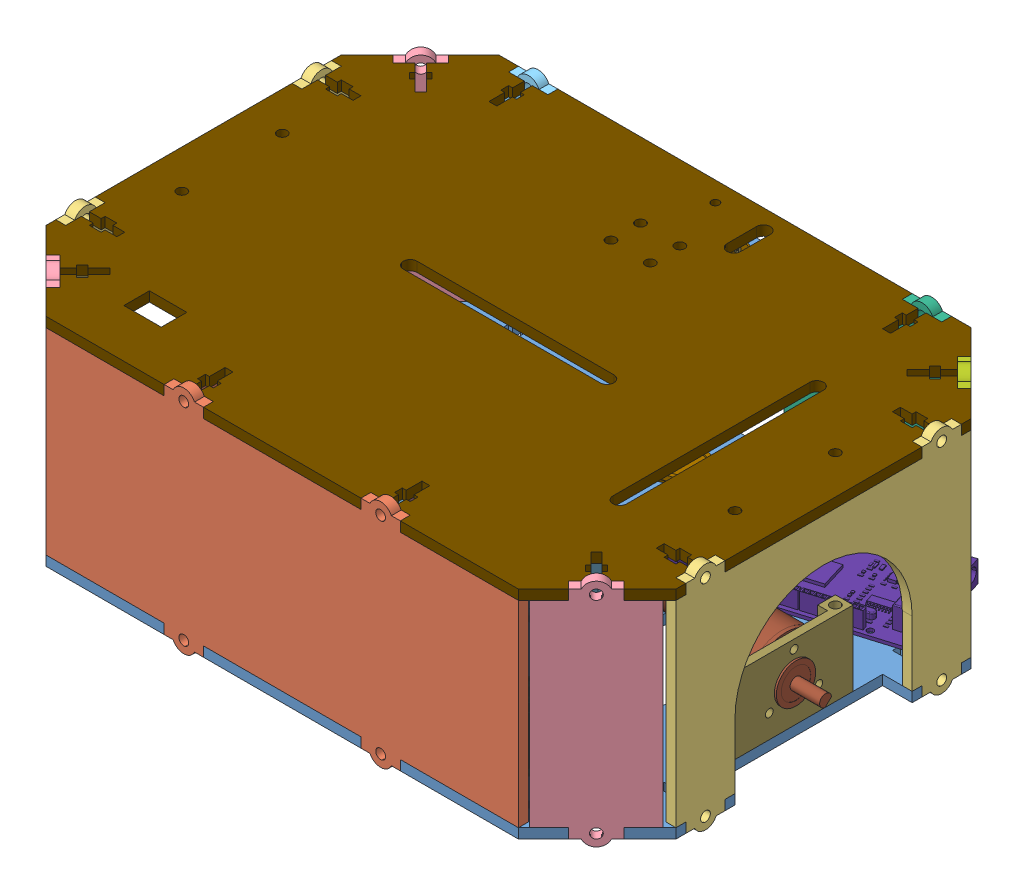
SolidWorks assembly Conception finale, configuration Default. Lengths in mm.
Overall size (322 125.9 232.7).
149 component instances, 109 part files, 84 mates.
Components (placement in the parent):
- base-1: base [Default] at (144.9851 187.411 243.3033) size (320 5 230)
- backwall-1: backwall [Default] at (144.9851 242.411 353.3033) size (240 117 5)
- encoderwall-1: encoderwall [Default] at (-15.0149 242.411 243.3033) x (0 0 -1) z (1 0 0) size (150 117 5)
- encoderwall-2: encoderwall [Default] at (299.9851 242.411 243.3033) x (0 0 -1) z (1 0 0) size (150 117 5)
- coinwall-1: coinwall [Default] at (5.1861 242.411 338.5044) x (-0.707107 0 -0.707107) z (0.707107 0 -0.707107) size (48 117 5)
- coinwall-3: coinwall [Default] at (8.7216 242.411 151.6379) x (-0.707107 0 0.707107) z (-0.707107 0 -0.707107) size (48 117 5)
- frontwall-1: frontwall [Default] at (44.9851 242.411 128.3033) size (40 117 5)
- frontwallleft-1: frontwallleft [Default] at (219.9851 242.411 133.3033) x (-1 0 0) z (0 0 -1) size (90 117 5)
- coinwallarduino-1: coinwallarduino [Default] at (284.7841 242.411 148.1023) x (0.707107 0 0.707107) z (-0.707107 0 0.707107) size (48 88.5 5)
- coinwall-5: coinwall [Default] at (281.2485 242.411 334.9688) x (0.707107 0 -0.707107) z (0.707107 0 0.707107) size (48 117 5)
- scroller support-1: scroller support [Default] at (144.9336 182.411 158.2438) x (0.999996 0 -0.002768) z (0.002768 0 0.999996) size (63 5 43)
- scroller support-2: scroller support [Default] at (144.9336 182.411 328.3568) x (0.999997 0 0.002484) z (-0.002484 0 0.999997) size (63 5 43)
- W420 Universal Steel Ball Caster-1: W420 Universal Steel Ball Caster [Default] at (126.0797 215.1451 204.8926) x (0.999966 0 -0.008254) z (-0.008254 0 -0.999966) size (50.67 20.4 23.62)
  - plastic stand-1: plastic stand [Default] at (18.2421 19.7342 46.6095) x (1 0 0) z (0 1 0) size (50.67 23.62 17.5)
  - ball-1: ball [Default] at (18.2421 32.6342 46.6095) size (15 15 15)
- W420 Universal Steel Ball Caster-2: W420 Universal Steel Ball Caster [Default] at (126.0357 215.1451 374.895) x (0.999973 0 -0.007309) z (-0.007309 0 -0.999973) size (50.67 20.4 23.62)
  - plastic stand-1: plastic stand [Default] at (18.2421 19.7342 46.6095) x (1 0 0) z (0 1 0) size (50.67 23.62 17.5)
  - ball-1: ball [Default] at (18.2421 32.6342 46.6095) size (15 15 15)
- Encoder - YUMO E6B2-CWZ3E-1: Encoder - YUMO E6B2-CWZ3E [Default] at (3.9851 211.411 243.3033) x (0 0.688167 -0.725552) z (1 0 0) size (40 72 59.05)
- support encoder-1: support encoder [Défaut] at (-4.8153 200.5473 210.7418) x (0 0 1) z (0 -1 0) size (60 9 38)
- Encoder - YUMO E6B2-CWZ3E-2: Encoder - YUMO E6B2-CWZ3E [Default] at (285.9851 211.411 243.3033) x (0 -0.688167 0.725552) z (-1 0 0) size (40 72 59.05)
- support encoder-2: support encoder [Défaut] at (294.7855 222.2747 210.7418) x (0 0 1) z (0 1 0) size (60 9 38)
- dc-1: dc [Default] at (184.7554 215.4273 248.1083) x (-0.00085 0.96122 -0.275783) z (0.999995 0 -0.003082) size (25 25 65.5)
- L-2: L [Default] at (176.0083 192.411 265.2813) x (-0.999995 0 0.003082) z (-0.003082 0 -0.999995) size (31 40 30)
- dc-2: dc [Default] at (105.2148 215.4273 248.1083) x (0.00085 0.96122 -0.275783) z (-0.999995 0 -0.003082) size (25 25 65.5)
- L-3: L [Default] at (114.0543 192.411 235.2815) x (0.999995 0 0.003082) z (-0.003082 0 0.999995) size (31 40 30)
- L298N Motor Driver.step-1: L298N Motor Driver.step [Default] at (232.0699 192.411 311.1269) x (0.999844 0 0.017659) z (-0.017659 0 0.999844) size (43.5 26 43.5)
- 3 Battery Holder With Batteries.step-1: 3 Battery Holder With Batteries.step [Default] at (69.3789 192.411 398.8726) x (1 0 0) z (0 1 0) size (77.98 59.63 24.74)
- Arduino_Mega.step-1: Arduino_Mega.step [Default] at (269.8515 192.411 130.3971) x (-0.957328 0 0.289003) z (-0.289003 0 -0.957328) size (109.3 15.6 54)
- s9af-1: s9af [Default] at (144.9851 292.411 243.3033) size (320 5 230)
- camsupport2-1: camsupport2 [Default] at (144.9851 259.911 156.3033) x (0 -1 0) z (1 0 0) size (55 63 40.58)
- ESP32-cam.step-1: ESP32-cam.step [Default] at (159.1738 242.9456 134.2033) x (-0.999726 -0.02341 0) z (0 0 -1) size (27 40 16.8)
  - pins.step-1: pins.step [Default] at origin size (25.4 20.32 11.2)
    - Body001.step-1: Body001.step [Default] at (2.07 17.64 0) size (2.54 2.54 11.2)
    - Body001.step-2: Body001.step [Default] at (2.07 20.18 0) size (2.54 2.54 11.2)
    - Body001.step-3: Body001.step [Default] at (2.07 22.72 0) size (2.54 2.54 11.2)
    - Body001.step-4: Body001.step [Default] at (2.07 25.26 0) size (2.54 2.54 11.2)
    - Body001.step-5: Body001.step [Default] at (2.07 27.8 0) size (2.54 2.54 11.2)
    - Body001.step-6: Body001.step [Default] at (2.07 30.34 0) size (2.54 2.54 11.2)
    - Body001.step-7: Body001.step [Default] at (2.07 32.88 0) size (2.54 2.54 11.2)
    - Body001.step-8: Body001.step [Default] at (2.07 35.42 0) size (2.54 2.54 11.2)
    - Body001.step-9: Body001.step [Default] at (24.93 17.64 0) size (2.54 2.54 11.2)
    - Body001.step-10: Body001.step [Default] at (24.93 20.18 0) size (2.54 2.54 11.2)
    - Body001.step-11: Body001.step [Default] at (24.93 22.72 0) size (2.54 2.54 11.2)
    - Body001.step-12: Body001.step [Default] at (24.93 25.26 0) size (2.54 2.54 11.2)
    - Body001.step-13: Body001.step [Default] at (24.93 27.8 0) size (2.54 2.54 11.2)
    - Body001.step-14: Body001.step [Default] at (24.93 30.34 0) size (2.54 2.54 11.2)
    - Body001.step-15: Body001.step [Default] at (24.93 32.88 0) size (2.54 2.54 11.2)
    - Body001.step-16: Body001.step [Default] at (24.93 35.42 0) size (2.54 2.54 11.2)
  - ESP32-S.step-1: ESP32-S.step [Default] at (4.5 25.2 0) x (1 0 0) z (0 0 -1) size (18 19.2 3.2)
    - PCB_ESP32-S.step-1: PCB_ESP32-S.step [Default] at origin size (18 19.2 2.02)
      - DesignRootModel^PCB_ESP32-S2-SOLO-U_V1_ESP32-S2-SOLO-U_V1.step-1: DesignRootModel^PCB_ESP32-S2-SOLO-U_V1_ESP32-S2-SOLO-U_V1.step [Default] at origin size (18 19.2 0.73)
        - uid__2363^DesignRootModel_PCB_ESP32-S2-SOLO-U_V1_ESP32-S2-SOLO-U_V1.step-1: uid__2363^DesignRootModel_PCB_ESP32-S2-SOLO-U_V1_ESP32-S2-SOLO-U_V1.step [Default] at origin size (18 19.2 0.73)
      - Submodel-IPEX_3P_part^DesignRootModel_PCB_ESP32-S2-SOLO-U_V1_ESP32-S2-SOLO-U_V1.step-1: Submodel-IPEX_3P_part^DesignRootModel_PCB_ESP32-S2-SOLO-U_V1_ESP32-S2-SOLO-U_V1.step [Default] at (15.0063 16.7434 0.7992) x (0 -1 0) z (0 0 1) size (3.01 3.11 1.26)
        - 20279-001E-01C RECEPTACLE R9 STEP ALL.STEP^Submodel-IPEX_3P_part_DesignRootModel_PCB_ESP32-S2-SOLO-U_V1_ESP32-S2-SOLO-U_V1.step-1: 20279-001E-01C RECEPTACLE R9 STEP ALL.STEP^Submodel-IPEX_3P_part_DesignRootModel_PCB_ESP32-S2-SOLO-U_V1_ESP32-S2-SOLO-U_V1.step [Default] x (1 0 0) z (0 -1 0) size (3.01 1.26 3.11)
          - 20279-001E-01C RECEPTACLE R9 STEP ALL.STEP^20279-001E-01C RECEPTACLE R9 STEP ALL.STEP_Submodel-IPEX_3P_part_DesignRootModel_PCB_ESP32-S2-SOLO-U_V1_ESP32-S2-SOLO-U_V003.step-1: 20279-001E-01C RECEPTACLE R9 STEP ALL.STEP^20279-001E-01C RECEPTACLE R9 STEP ALL.STEP_Submodel-IPEX_3P_part_DesignRootModel_PCB_ESP32-S2-SOLO-U_V1_ESP32-S2-SOLO-U_V003.step [Default] at origin size (3.01 1.26 3.11)
            - 20279-001E-01C RECEPTACLE R9 STEP ALL.STEP^20279-001E-01C RECEPTACLE R9 STEP ALL.STEP_Submodel-IPEX_3P_part_DesignRootModel_PCB_ESP32-S2-SOLO-U_V1_ESP32-S2-SOLO-U_V1.step-1: 20279-001E-01C RECEPTACLE R9 STEP ALL.STEP^20279-001E-01C RECEPTACLE R9 STEP ALL.STEP_Submodel-IPEX_3P_part_DesignRootModel_PCB_ESP32-S2-SOLO-U_V1_ESP32-S2-SOLO-U_V1.step [Default] at origin size (2.61 0.01 2.61)
            - 20279-001E-01C RECEPTACLE R9 STEP ALL.STEP^20279-001E-01C RECEPTACLE R9 STEP ALL.STEP_Submodel-IPEX_3P_part_DesignRootModel_PCB_ESP32-S2-SOLO-U_V1_ESP32-S2-SOLO-U_V002.step-1: 20279-001E-01C RECEPTACLE R9 STEP ALL.STEP^20279-001E-01C RECEPTACLE R9 STEP ALL.STEP_Submodel-IPEX_3P_part_DesignRootModel_PCB_ESP32-S2-SOLO-U_V1_ESP32-S2-SOLO-U_V002.step [Default] at origin size (3.01 1.26 3.11)
      - uid__1-263^DesignRootModel_PCB_ESP32-S2-SOLO-U_V1_ESP32-S2-SOLO-U_V1.step-1: uid__1-263^DesignRootModel_PCB_ESP32-S2-SOLO-U_V1_ESP32-S2-SOLO-U_V1.step [Default] at origin size (2.2 0.95 0.03)
      - uid__1-264^DesignRootModel_PCB_ESP32-S2-SOLO-U_V1_ESP32-S2-SOLO-U_V1.step-1: uid__1-264^DesignRootModel_PCB_ESP32-S2-SOLO-U_V1_ESP32-S2-SOLO-U_V1.step [Default] at origin size (2.2 0.95 0.03)
    - pad.step-1: pad.step [Default] at (0 18.01 0.0349) x (1 0 0) z (0 -1 0) size (0.85 0.8 0.9)
    - pad001.step-1: pad001.step [Default] at (0 16.74 0.0349) x (1 0 0) z (0 -1 0) size (0.85 0.8 0.9)
    - pad002.step-1: pad002.step [Default] at (0 15.47 0.0349) x (1 0 0) z (0 -1 0) size (0.85 0.8 0.9)
    - pad003.step-1: pad003.step [Default] at (0 14.2 0.0349) x (1 0 0) z (0 -1 0) size (0.85 0.8 0.9)
    - pad004.step-1: pad004.step [Default] at (0 12.93 0.0349) x (1 0 0) z (0 -1 0) size (0.85 0.8 0.9)
    - pad005.step-1: pad005.step [Default] at (0 11.66 0.0349) x (1 0 0) z (0 -1 0) size (0.85 0.8 0.9)
    - pad006.step-1: pad006.step [Default] at (0 10.39 0.0349) x (1 0 0) z (0 -1 0) size (0.85 0.8 0.9)
    - pad007.step-1: pad007.step [Default] at (0 9.12 0.0349) x (1 0 0) z (0 -1 0) size (0.85 0.8 0.9)
    - pad008.step-1: pad008.step [Default] at (0 7.85 0.0349) x (1 0 0) z (0 -1 0) size (0.85 0.8 0.9)
    - pad009.step-1: pad009.step [Default] at (0 6.58 0.0349) x (1 0 0) z (0 -1 0) size (0.85 0.8 0.9)
    - pad010.step-1: pad010.step [Default] at (0 5.31 0.0349) x (1 0 0) z (0 -1 0) size (0.85 0.8 0.9)
    - pad011.step-1: pad011.step [Default] at (0 4.04 0.0349) x (1 0 0) z (0 -1 0) size (0.85 0.8 0.9)
    - pad012.step-1: pad012.step [Default] at (0 2.77 0.0349) x (1 0 0) z (0 -1 0) size (0.85 0.8 0.9)
    - pad013.step-1: pad013.step [Default] at (0 1.5 0.0349) x (1 0 0) z (0 -1 0) size (0.85 0.8 0.9)
    - pad014.step-1: pad014.step [Default] at (2.015 0 0.0343) x (0 1 0) z (1 0 0) size (0.85 0.8 0.9)
    - pad015.step-1: pad015.step [Default] at (3.285 0 0.0343) x (0 1 0) z (1 0 0) size (0.85 0.8 0.9)
    - pad016.step-1: pad016.step [Default] at (4.555 0 0.0343) x (0 1 0) z (1 0 0) size (0.85 0.8 0.9)
    - pad017.step-1: pad017.step [Default] at (5.825 0 0.0343) x (0 1 0) z (1 0 0) size (0.85 0.8 0.9)
    - pad018.step-1: pad018.step [Default] at (7.095 0 0.0343) x (0 1 0) z (1 0 0) size (0.85 0.8 0.9)
    - pad019.step-1: pad019.step [Default] at (8.365 0 0.0343) x (0 1 0) z (1 0 0) size (0.85 0.8 0.9)
    - pad020.step-1: pad020.step [Default] at (9.635 0 0.0343) x (0 1 0) z (1 0 0) size (0.85 0.8 0.9)
    - pad021.step-1: pad021.step [Default] at (10.905 0 0.0343) x (0 1 0) z (1 0 0) size (0.85 0.8 0.9)
    - pad022.step-1: pad022.step [Default] at (12.175 0 0.0343) x (0 1 0) z (1 0 0) size (0.85 0.8 0.9)
    - pad023.step-1: pad023.step [Default] at (13.445 0 0.0343) x (0 1 0) z (1 0 0) size (0.85 0.8 0.9)
    - pad024.step-1: pad024.step [Default] at (14.715 0 0.0343) x (0 1 0) z (1 0 0) size (0.85 0.8 0.9)
    - pad025.step-1: pad025.step [Default] at (15.985 0 0.0343) x (0 1 0) z (1 0 0) size (0.85 0.8 0.9)
    - pad026.step-1: pad026.step [Default] at (18 1.5 0.0343) x (-1 0 0) z (0 1 0) size (0.85 0.8 0.9)
    - pad027.step-1: pad027.step [Default] at (18 2.77 0.0343) x (-1 0 0) z (0 1 0) size (0.85 0.8 0.9)
    - pad028.step-1: pad028.step [Default] at (18 4.04 0.0343) x (-1 0 0) z (0 1 0) size (0.85 0.8 0.9)
    - pad029.step-1: pad029.step [Default] at (18 5.31 0.0343) x (-1 0 0) z (0 1 0) size (0.85 0.8 0.9)
    - pad030.step-1: pad030.step [Default] at (18 6.58 0.0343) x (-1 0 0) z (0 1 0) size (0.85 0.8 0.9)
    - pad031.step-1: pad031.step [Default] at (18 7.85 0.0343) x (-1 0 0) z (0 1 0) size (0.85 0.8 0.9)
    - pad032.step-1: pad032.step [Default] at (18 9.12 0.0343) x (-1 0 0) z (0 1 0) size (0.85 0.8 0.9)
    - pad033.step-1: pad033.step [Default] at (18 10.39 0.0343) x (-1 0 0) z (0 1 0) size (0.85 0.8 0.9)
    - pad034.step-1: pad034.step [Default] at (18 11.66 0.0343) x (-1 0 0) z (0 1 0) size (0.85 0.8 0.9)
    - pad035.step-1: pad035.step [Default] at (18 12.93 0.0343) x (-1 0 0) z (0 1 0) size (0.85 0.8 0.9)
    - pad036.step-1: pad036.step [Default] at (18 14.2 0.0343) x (-1 0 0) z (0 1 0) size (0.85 0.8 0.9)
    - pad037.step-1: pad037.step [Default] at (18 15.47 0.0343) x (-1 0 0) z (0 1 0) size (0.85 0.8 0.9)
    - pad038.step-1: pad038.step [Default] at (18 16.74 0.0343) x (-1 0 0) z (0 1 0) size (0.85 0.8 0.9)
    - pad039.step-1: pad039.step [Default] at (18 18.01 0.0343) x (-1 0 0) z (0 1 0) size (0.85 0.8 0.9)
    - ESP32-WROOM-32U_Shieldingcase_20210312.step-1: ESP32-WROOM-32U_Shieldingcase_20210312.step [Default] at (1.27 1.1 0.7993) size (15.65 17.5 2.4)
  - MicroSD slot SMD.step-1: MicroSD slot SMD.step [Default] at (13.5 32.5 0.9) size (17.2 14.8 1.8)
    - Array.step-1: Array.step [Default] at origin size (9.49 0.5 0.62)
      - Body003.step-1: Body003.step [Default] at (-3 -7 0.075) size (0.6 0.5 0.62)
      - Body004.step-1: Body004.step [Default] at (-1.73 -7 0.075) size (0.6 0.5 0.62)
      - Body005.step-1: Body005.step [Default] at (-0.46 -7 0.075) size (0.6 0.5 0.62)
      - Body006.step-1: Body006.step [Default] at (0.81 -7 0.075) size (0.6 0.5 0.62)
      - Body007.step-1: Body007.step [Default] at (2.08 -7 0.075) size (0.6 0.5 0.62)
      - Body008.step-1: Body008.step [Default] at (3.35 -7 0.075) size (0.6 0.5 0.62)
      - Body009.step-1: Body009.step [Default] at (4.62 -7 0.075) size (0.6 0.5 0.62)
      - Body010.step-1: Body010.step [Default] at (5.89 -7 0.075) size (0.6 0.5 0.62)
    - Body.step-1: Body.step [Default] at origin size (17.2 14.8 1.8)
    - Body002.step-1: Body002.step [Default] at origin size (14.5 14.65 1.5)
  - FPC 24.step-1: FPC 24.step [Default] at (19.5 11 0.9) x (-1 0 0) z (0 0 1) size (16.3 5.85 2.11)
    - FPC-24.step-1: FPC-24.step [Default] at origin size (0.5 4.5 2.1)
    - FPC-025.step-1: FPC-025.step [Default] at origin size (1.55 2.65 1.85)
    - FPC-026.step-1: FPC-026.step [Default] at origin size (0.71 4.5 2.1)
    - FPC-027.step-1: FPC-027.step [Default] at origin size (1.45 2.4 1.6)
    - FPC-028.step-1: FPC-028.step [Default] at origin size (0.3 0.4 1.6)
    - FPC-029.step-1: FPC-029.step [Default] at origin size (0.3 0.7 0.7)
    - FPC-030.step-1: FPC-030.step [Default] at origin size (13.65 5.85 2.11)
    - FPC-031.step-1: FPC-031.step [Default] at origin size (1.05 4.5 0.8)
    - FPC-032.step-1: FPC-032.step [Default] at origin size (1.05 4.5 0.2)
    - FPC-033.step-1: FPC-033.step [Default] at origin size (0.4 4.5 1.9)
    - FPC-034.step-1: FPC-034.step [Default] at origin size (0.2 4.5 1.6)
    - FPC-035.step-1: FPC-035.step [Default] at origin size (1.55 4.5 1.85)
    - FPC-036.step-1: FPC-036.step [Default] at origin size (0.69 2.75 0.2)
    - FPC-037.step-1: FPC-037.step [Default] at origin size (0.15 4.5 0.6)
    - FPC-038.step-1: FPC-038.step [Default] at origin size (0.15 4.5 0.2)
    - FPC-039.step-1: FPC-039.step [Default] at origin size (0.4 4.5 1.9)
    - FPC-040.step-1: FPC-040.step [Default] at origin size (0.2 4.5 1.6)
  - OV2640 camera.step-1: OV2640 camera.step [Default] at (13.5 29.5 2.8) size (8.31 8.06 5.8)
    - Body011.step-1: Body011.step [Default] at origin size (8.31 8.06 5.8)
    - Body012.step-1: Body012.step [Default] at origin size (2.52 2.52 0.25)
  - Flash LED.step-1: Flash LED.step [Default] at (25 10 0.9) size (3 3 0.6)
    - Body018.step-1: Body018.step [Default] at origin size (3 3 0.6)
    - Body019.step-1: Body019.step [Default] at origin size (2.8 2.8 0.3)
    - Body020.step-1: Body020.step [Default] at origin size (2.75 2.75 0.2)
  - PCB.step-1: PCB.step [Default] at origin size (27 40 0.9)
  - WiFi antenna.step-1: WiFi antenna.step [Default] at (19.5 5.6 0) x (1 0 0) z (0 0 -1) size (18 6 0.8)
  - SOIC_8_1EP_39x49mm_P127mm.step-1: SOIC_8_1EP_39x49mm_P127mm.step [Default] at (20.5 34.5 0) x (0 -1 0) z (0 0 -1) size (6 4.9 1.75)
  - SW_SPST_B3U-1000P.step-1: SW_SPST_B3U-1000P.step [Default] at (5.7 36.5 0) x (0 1 0) z (0 0 -1) size (4 2.51 1.59)
  - SOT_223.step-1: SOT_223.step [Default] at (12.3 35 0) x (0 1 0) z (0 0 -1) size (7 6.5 1.7)
  - CP_EIA_3528_12_Kemet_T.step-1: CP_EIA_3528_12_Kemet_T.step [Default] at (6 30 0) x (0 -1 0) z (0 0 -1) size (3.7 3 1.2)
  - scotxh.step-1: scotxh.step [Default] at (13.5 29.5 2.7) size (8.2 8.2 0.1)
  - Body014.step-1: Body014.step [Default] at origin size (12 12.5 1.6)
  - SOT_23-1.step-1: SOT_23-1.step [Default] at (3.3 14.7 0.9) x (0 1 0) z (0 0 1) size (2.5 3 1.2)
  - SOT_23-2.step-1: SOT_23-2.step [Default] at (25.4 14 0.9) x (0 1 0) z (0 0 1) size (2.5 3 1.2)
  - Text.step-1: Text.step [Default] at origin size (19 3.5 0.42)
Mates (geometry in assembly coordinates):
- Coincident16: coincident anti-aligned: plane of prototype1_base1-1 through (144.9851 192.411 243.3033) normal (0 1 0); plane of ArduinoMega-2 through (276.717 192.411 128.0607) normal (0 -1 0)
- Coincident17: coincident anti-aligned: plane of prototype1_base1-1 through (144.9851 192.411 243.3033) normal (0 1 0); plane of L298N Stepper drive-1 through (148.4735 192.411 198.6187) normal (0 -1 0)
- Distance1: distance = 5 mm aligned: plane of servo+support-1/support servo-1 through (105.1361 197.411 133.3033) normal (0 0 -1); plane of prototype1_base1-1 through (304.9851 192.411 128.3033) normal (0 0 -1)
- Coincident20: coincident anti-aligned: plane of prototype1_base1-1 through (144.9851 192.411 243.3033) normal (0 1 0); plane of servo+support-1/support servo-1 through (95.1361 192.411 150.8033) normal (0 -1 0)
- Coincident21: coincident anti-aligned: plane of prototype1_base1-1 through (144.9851 192.411 243.3033) normal (0 1 0); plane of battery_holder.step-1 through (221.2091 192.411 308.7692) normal (0 -1 0)
- Width1: width anti-aligned: plane of encodeur-support-1 through (-0.0149 232.5931 273.3033) normal (0 0 1); plane of prototype1_base1-1 through (-0.0149 232.5931 213.3033) normal (0 0 -1); plane of encodeur-support-1 through (-15.0149 187.411 288.3033) normal (0 0 -1); plane of prototype1_base1-1 through (-15.0149 187.411 198.3033) normal (0 0 1)
- Coincident24: coincident aligned: plane of prototype1_base1-1 through (-0.0149 187.411 198.3033) normal (-1 0 0); plane of encodeur-support-1 through (-0.0149 232.5931 273.3033) normal (-1 0 0)
- Concentric2: concentric aligned: cylinder of encodeur-support-1 through (4.4851 232.5931 217.8033) axis (0 -1 0) radius 2.5; cylinder of tige-1 through (4.4851 241.5741 217.8033) axis (0 -1 0) radius 1.1
- Concentric3: concentric aligned: cylinder of encodeur-support-1 through (4.4851 232.5931 268.8033) axis (0 -1 0) radius 2.5; cylinder of tige-2 through (4.4851 242.0721 268.8033) axis (0 -1 0) radius 1.1
- Coincident34: coincident anti-aligned: plane of prototype1_base1-1 through (144.9851 192.411 243.3033) normal (0 1 0); plane of JGB37-520-1/support motor-1 through (205.9851 192.411 223.8033) normal (0 -1 0)
- Width3: width anti-aligned: plane of JGB37-520-1/support motor-1 through (205.9851 192.411 223.8033) normal (0 0 -1); plane of JGB37-520-1/support motor-1 through (205.9851 192.411 262.8033) normal (0 0 1); plane of prototype1_base1-1 through (247.9851 187.411 205.8033) normal (0 0 1); plane of prototype1_base1-1 through (247.9851 187.411 280.8033) normal (0 0 -1)
- Coincident35: coincident aligned: plane of prototype1_base1-1 through (207.9851 187.411 205.8033) normal (1 0 0); plane of JGB37-520-1/support motor-1 through (207.9851 219.5706 243.3026) normal (1 0 0)
- Coincident37: coincident anti-aligned: plane of prototype1_base1-1 through (144.9851 192.411 243.3033) normal (0 1 0); plane of battery_holder.step-2 through (56.2097 192.411 316.6119) normal (0 -1 0)
- Width6: width aligned: plane of base2-1/prototype1_base2-1 through (-15.0149 297.411 358.3033) normal (-1 0 0); plane of prototype1_base1-1 through (304.9851 297.411 358.3033) normal (1 0 0); plane of base2-1/prototype1_base2-1 through (-15.0149 192.411 358.3033) normal (-1 0 0); plane of prototype1_base1-1 through (304.9851 192.411 358.3033) normal (1 0 0)
- Width7: width aligned: plane of base2-1/prototype1_base2-1 through (304.9851 297.411 358.3033) normal (0 0 1); plane of prototype1_base1-1 through (304.9851 297.411 128.3033) normal (0 0 -1); plane of base2-1/prototype1_base2-1 through (304.9851 192.411 358.3033) normal (0 0 1); plane of prototype1_base1-1 through (304.9851 192.411 128.3033) normal (0 0 -1)
- Distance3: distance = 100 mm anti-aligned: plane of prototype1_base1-1 through (144.9851 192.411 243.3033) normal (0 1 0); plane of base2-1/prototype1_base2-1 through (144.9851 292.411 243.3033) normal (0 -1 0)
- Coincident40: coincident anti-aligned: plane of base2-1/prototype1_base2-1 through (104.9851 287.411 353.3033) normal (0 0 1); plane of backwall-1 through (144.9851 242.411 353.3033) normal (0 0 -1)
- Coincident41: coincident anti-aligned: plane of base2-1/prototype1_base2-1 through (104.9851 287.411 358.3033) normal (-1 0 0); plane of backwall-1 through (104.9851 297.411 353.3033) normal (1 0 0)
- Coincident42: coincident aligned: plane of base2-1/prototype1_base2-1 through (144.9851 297.411 243.3033) normal (0 1 0); plane of backwall-1 through (144.9851 297.411 353.3033) normal (0 1 0)
- Coincident43: coincident anti-aligned: plane of base2-1/prototype1_base2-1 through (-10.0149 287.411 243.3033) normal (-1 0 0); plane of encoderwall-1 through (-10.0149 242.411 243.3033) normal (1 0 0)
- Coincident44: coincident anti-aligned: plane of base2-1/prototype1_base2-1 through (144.9851 287.411 193.3033) normal (0 0 -1); plane of encoderwall-1 through (-15.0149 297.411 193.3033) normal (0 0 1)
- Coincident45: coincident anti-aligned: plane of base2-1/prototype1_base2-1 through (144.9851 292.411 243.3033) normal (0 -1 0); plane of encoderwall-1 through (-10.0149 292.411 168.3033) normal (0 1 0)
- Coincident46: coincident anti-aligned: plane of base2-1/prototype1_base2-1 through (299.9851 287.411 243.3033) normal (1 0 0); plane of encoderwall-2 through (299.9851 242.411 243.3033) normal (-1 0 0)
- Coincident47: coincident anti-aligned: plane of base2-1/prototype1_base2-1 through (144.9851 292.411 243.3033) normal (0 -1 0); plane of encoderwall-2 through (304.9851 292.411 168.3033) normal (0 1 0)
- Coincident48: coincident anti-aligned: plane of base2-1/prototype1_base2-1 through (144.9851 287.411 313.3033) normal (0 0 -1); plane of encoderwall-2 through (299.9851 297.411 313.3033) normal (0 0 1)
- Coincident49: coincident anti-aligned: plane of base2-1/prototype1_base2-1 through (31.0206 287.411 357.2678) normal (-0.707107 0 0.707107); plane of coinwall-1 through (8.7216 242.411 334.9688) normal (0.707107 0 -0.707107)
- Coincident50: coincident anti-aligned: plane of base2-1/prototype1_base2-1 through (129.7572 287.411 228.0754) normal (-0.707107 0 -0.707107); plane of coinwall-1 through (15.7927 297.411 342.0399) normal (0.707107 0 0.707107)
- Coincident51: coincident anti-aligned: plane of base2-1/prototype1_base2-1 through (144.9851 292.411 243.3033) normal (0 -1 0); plane of coinwall-1 through (-8.2489 292.411 317.9983) normal (0 1 0)
- Coincident56: coincident anti-aligned: plane of base2-1/prototype1_base2-1 through (129.7572 287.411 258.5313) normal (-0.707107 0 0.707107); plane of coinwall-3 through (12.2572 297.411 141.0313) normal (0.707107 0 -0.707107)
- Coincident59: coincident anti-aligned: plane of base2-1/prototype1_base2-1 through (129.7572 287.411 258.5313) normal (-0.707107 0 0.707107); plane of coinwall-3 through (12.2572 297.411 141.0313) normal (0.707107 0 -0.707107)
- Coincident60: coincident anti-aligned: plane of base2-1/prototype1_base2-1 through (115.615 287.411 272.6734) normal (0.707107 0 -0.707107); plane of coinwall-3 through (-1.885 297.411 155.1734) normal (-0.707107 0 0.707107)
- Coincident61: coincident anti-aligned: plane of base2-1/prototype1_base2-1 through (31.0206 287.411 129.3389) normal (-0.707107 0 -0.707107); plane of coinwall-3 through (8.7216 242.411 151.6379) normal (0.707107 0 0.707107)
- Coincident62: coincident anti-aligned: plane of base2-1/prototype1_base2-1 through (144.9851 292.411 243.3033) normal (0 -1 0); plane of coinwall-3 through (-11.7845 292.411 165.0729) normal (0 1 0)
- Coincident66: coincident anti-aligned: plane of base2-1/prototype1_base2-1 through (54.9851 287.411 243.3033) normal (-1 0 0); plane of frontwall-1 through (54.9851 297.411 133.3033) normal (1 0 0)
- Coincident67: coincident anti-aligned: plane of base2-1/prototype1_base2-1 through (144.9851 287.411 133.3033) normal (0 0 -1); plane of frontwall-1 through (44.9851 242.411 133.3033) normal (0 0 1)
- Coincident68: coincident anti-aligned: plane of base2-1/prototype1_base2-1 through (144.9851 292.411 243.3033) normal (0 -1 0); plane of frontwall-1 through (64.9851 292.411 133.3033) normal (0 1 0)
- Concentric23: concentric aligned: cylinder of prototype1_base1-1 through (123.4337 182.411 158.3033) axis (0 1 0) radius 3.5; cylinder of roue libre-4/roue libre part 2-1 through (123.4337 197.482 158.3033) axis (0 1 0) radius 2.5
- Coincident69: coincident aligned: plane of base2-1/prototype1_base2-1 through (304.9851 297.411 128.3033) normal (0 0 -1); plane of frontwallleft-1 through (219.9851 242.411 128.3033) normal (0 0 -1)
- Coincident70: coincident anti-aligned: plane of base2-1/prototype1_base2-1 through (144.9851 292.411 243.3033) normal (0 -1 0); plane of frontwallleft-1 through (174.9851 292.411 128.3033) normal (0 1 0)
- Coincident71: coincident anti-aligned: plane of base2-1/prototype1_base2-1 through (234.9851 287.411 243.3033) normal (1 0 0); plane of frontwallleft-1 through (234.9851 297.411 128.3033) normal (-1 0 0)
- Coincident72: coincident anti-aligned: plane of base2-1/prototype1_base2-1 through (258.9496 287.411 129.3389) normal (0.707107 0 -0.707107); plane of coinwallarduino-1 through (281.2485 242.411 151.6379) normal (-0.707107 0 0.707107)
- Coincident73: coincident anti-aligned: plane of base2-1/prototype1_base2-1 through (174.3551 287.411 272.6734) normal (-0.707107 0 -0.707107); plane of coinwallarduino-1 through (288.3196 297.411 158.7089) normal (0.707107 0 0.707107)
- Coincident74: coincident anti-aligned: plane of base2-1/prototype1_base2-1 through (144.9851 292.411 243.3033) normal (0 -1 0); plane of coinwallarduino-1 through (298.2191 292.411 168.6084) normal (0 1 0)
- Coincident75: coincident anti-aligned: plane of base2-1/prototype1_base2-1 through (258.9496 287.411 357.2678) normal (0.707107 0 0.707107); plane of coinwall-5 through (281.2485 242.411 334.9688) normal (-0.707107 0 -0.707107)
- Coincident76: coincident anti-aligned: plane of base2-1/prototype1_base2-1 through (144.9851 292.411 243.3033) normal (0 -1 0); plane of coinwall-5 through (301.7546 292.411 321.5338) normal (0 1 0)
- Coincident77: coincident anti-aligned: plane of base2-1/prototype1_base2-1 through (174.3551 287.411 213.9333) normal (-0.707107 0 0.707107); plane of coinwall-5 through (291.8551 297.411 331.4333) normal (0.707107 0 -0.707107)
- Concentric24: concentric aligned: cylinder of base2-1/prototype1_base2-1 through (144.9851 289.411 138.3033) axis (0 1 0) radius 2; cylinder of led1-1/led support-1 through (144.9851 291.411 138.3033) axis (0 1 0) radius 2
- Coincident80: coincident anti-aligned: plane of base2-1/prototype1_base2-1 through (144.9851 297.411 243.3033) normal (0 1 0); plane of led1-1/led support-1 through (149.9851 297.411 134.3033) normal (0 -1 0)
- Parallel1: parallel aligned: plane of base2-1/prototype1_base2-1 through (304.9851 297.411 128.3033) normal (0 0 -1); plane of led1-1/led support-1 through (144.9851 302.411 129.3033) normal (0 0 -1)
- Coincident81: coincident anti-aligned: plane of prototype1_base1-1 through (144.9851 187.411 243.3033) normal (0 -1 0); plane of scroller support-1 through (134.1837 187.411 158.2736) normal (0 1 0)
- Concentric25: concentric anti-aligned: cylinder of prototype1_base1-1 through (123.4337 182.411 158.3033) axis (0 1 0) radius 3.5; cylinder of scroller support-1 through (123.4337 187.411 158.3033) axis (0 -1 0) radius 3.5
- Lock1: lock: unknown of prototype1_base1-1; unknown of scroller support-1
- Coincident82: coincident anti-aligned: plane of prototype1_base1-1 through (144.9851 187.411 243.3033) normal (0 -1 0); plane of scroller support-2 through (134.1837 187.411 328.33) normal (0 1 0)
- Concentric27: concentric anti-aligned: cylinder of prototype1_base1-1 through (123.4337 182.411 328.3033) axis (0 1 0) radius 3.5; cylinder of scroller support-2 through (123.4337 187.411 328.3033) axis (0 -1 0) radius 3.5
- Lock2: lock: unknown of prototype1_base1-1; unknown of scroller support-2
- Coincident83: coincident anti-aligned: plane of prototype1_base1-1 through (144.9851 192.411 243.3033) normal (0 1 0); plane of W420 Universal Steel Ball Caster-1/plastic stand-1 through (143.9365 192.411 158.1341) normal (0 -1 0)
- Concentric29: concentric aligned: cylinder of prototype1_base1-1 through (123.4337 182.411 158.3033) axis (0 1 0) radius 3.5; cylinder of W420 Universal Steel Ball Caster-1/plastic stand-1 through (123.4337 177.911 158.3033) axis (0 1 0) radius 1.55
- Lock3: lock: unknown of prototype1_base1-1; unknown of W420 Universal Steel Ball Caster-1/plastic stand-1
- Coincident86: coincident anti-aligned: plane of prototype1_base1-1 through (144.9851 192.411 243.3033) normal (0 1 0); plane of W420 Universal Steel Ball Caster-2/plastic stand-1 through (143.9367 192.411 328.1535) normal (0 -1 0)
- Concentric30: concentric aligned: cylinder of prototype1_base1-1 through (123.4337 182.411 328.3033) axis (0 1 0) radius 3.5; cylinder of W420 Universal Steel Ball Caster-2/plastic stand-1 through (123.4337 177.911 328.3033) axis (0 1 0) radius 1.55
- Lock4: lock: unknown of prototype1_base1-1; unknown of W420 Universal Steel Ball Caster-2/plastic stand-1
- Coincident87: coincident: plane of prototype1_base1-1 through (144.9851 192.411 243.3033) normal (0 1 0); plane of L-1 through (174.5302 192.411 229.6714) normal (0 -1 0)
- Concentric32: concentric aligned: cylinder of prototype1_base1-1 through (4.4851 182.411 268.8033) axis (0 1 0) radius 2.5; cylinder of support encoder-1 through (4.4851 192.411 268.8033) axis (0 1 0) radius 2.5
- Concentric33: concentric aligned: cylinder of prototype1_base1-1 through (4.4851 182.411 217.8033) axis (0 1 0) radius 2.5; cylinder of support encoder-1 through (4.4851 192.411 217.8033) axis (0 1 0) radius 2.5
- Coincident88: coincident anti-aligned: plane of prototype1_base1-1 through (144.9851 192.411 243.3033) normal (0 1 0); plane of support encoder-1 through (-0.0149 192.411 243.3033) normal (0 -1 0)
- Concentric34: concentric aligned: cylinder of Encoder - YUMO E6B2-CWZ3E-1 through (-1.0149 211.411 243.3033) axis (1 0 0) radius 10; cylinder of support encoder-1 through (-34.0149 211.411 243.3033) axis (1 0 0) radius 10
- Coincident90: coincident anti-aligned: plane of Encoder - YUMO E6B2-CWZ3E-1 through (3.9851 211.411 243.3033) normal (-1 0 0); plane of support encoder-1 through (3.9851 192.411 222.3033) normal (1 0 0)
- Coincident91: coincident anti-aligned: plane of prototype1_base1-1 through (144.9851 192.411 243.3033) normal (0 1 0); plane of L-2 through (175.9158 192.411 235.2815) normal (0 -1 0)
- Concentric35: concentric aligned: cylinder of prototype1_base1-1 through (196.9851 182.411 257.7166) axis (0 1 0) radius 2.25; cylinder of L-2 through (196.9851 192.411 257.7166) axis (0 1 0) radius 2
- Coincident92: coincident aligned: circle of dc-1; plane of L-2 through (203.9157 195.411 235.1952) normal (-0.999995 0 0.003082)
- Parallel7: parallel aligned: plane of dc-1 through (206.4553 215.4273 248.0414) normal (0.999995 0 -0.003082); plane of L-2 through (206.9157 192.411 235.1859) normal (0.999995 0 -0.003082)
- Coincident95: coincident anti-aligned: plane of prototype1_base1-1 through (144.9851 192.411 243.3033) normal (0 1 0); plane of L298N Motor Driver.step-1 through (232.0699 192.411 311.1269) normal (0 -1 0)
- Coincident96: coincident anti-aligned: plane of prototype1_base1-1 through (144.9851 192.411 243.3033) normal (0 1 0); plane of 3 Battery Holder With Batteries.step-1 through (69.3789 192.411 312.8726) normal (0 -1 0)
- Coincident97: coincident anti-aligned: plane of prototype1_base1-1 through (144.9851 192.411 243.3033) normal (0 1 0); plane of Arduino_Mega.step-1 through (269.8515 192.411 130.3971) normal (0 -1 0)
- Coincident99: coincident anti-aligned: plane of prototype1_base1-1 through (144.9851 192.411 243.3033) normal (0 1 0); plane of backwall-1 through (264.9851 192.411 358.3033) normal (0 -1 0)
- Coincident100: coincident anti-aligned: plane of prototype1_base1-1 through (144.9851 182.411 353.3033) normal (0 0 1); plane of backwall-1 through (144.9851 242.411 353.3033) normal (0 0 -1)
- Coincident101: coincident anti-aligned: plane of prototype1_base1-1 through (104.9851 182.411 243.3033) normal (-1 0 0); plane of backwall-1 through (104.9851 187.411 353.3033) normal (1 0 0)
- Coincident102: coincident anti-aligned: plane of backwall-1 through (264.9851 292.411 358.3033) normal (0 1 0); plane of prototype1_base2-1 through (144.9851 292.411 243.3033) normal (0 -1 0)
- Coincident103: coincident anti-aligned: plane of backwall-1 through (84.9851 297.411 353.3033) normal (-1 0 0); plane of prototype1_base2-1 through (84.9851 287.411 358.3033) normal (1 0 0)
- Coincident104: coincident anti-aligned: plane of prototype1_base2-1 through (144.9851 292.411 243.3033) normal (0 -1 0); plane of camsupport2-1 through (144.9851 292.411 156.3033) normal (0 1 0)
- Concentric36: concentric aligned: cylinder of prototype1_base2-1 through (154.9851 287.411 166.3033) axis (0 1 0) radius 2.5; cylinder of camsupport2-1 through (154.9851 265.411 166.3033) axis (0 1 0) radius 2.5
- Concentric37: concentric aligned: cylinder of prototype1_base2-1 through (134.9851 287.411 166.3033) axis (0 1 0) radius 2.5; cylinder of camsupport2-1 through (134.9851 265.411 166.3033) axis (0 1 0) radius 2.5
- Coincident107: coincident anti-aligned: plane of backwall-1 through (144.9851 242.411 353.3033) normal (0 0 -1); plane of prototype1_base2-1 through (104.9851 287.411 353.3033) normal (0 0 1)
- Coincident108: coincident anti-aligned: plane of camsupport2-1 through (129.9851 242.411 133.3033) normal (0 0 1); plane of ESP32-cam.step-1/PCB.step-1 through (145.2093 262.6241 133.3033) normal (0 0 -1)
